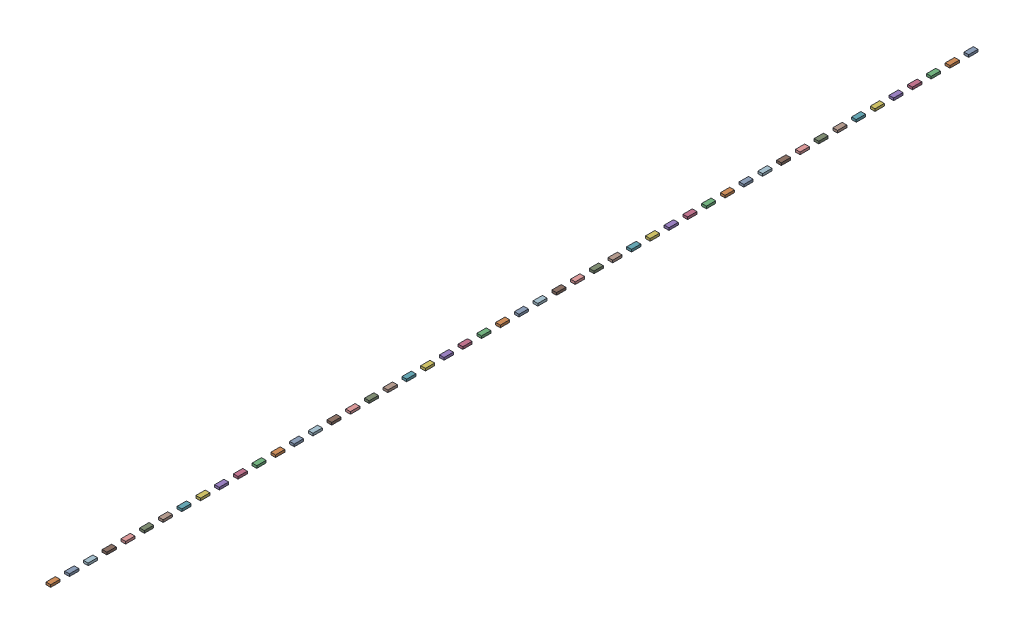
SolidWorks assembly lane_track_01, configuration Default. Lengths in mm.
Overall size (50 25 9900).
50 component instances, 1 part files, 0 mates.
Components (placement in the parent):
- lane-1: lane [Default] at (13.0249 -24.3771 9.6884) size (50 25 100)
- lane-2: lane [Default] at (13.0249 -24.3771 209.6884) size (50 25 100)
- lane-3: lane [Default] at (13.0249 -24.3771 409.6884) size (50 25 100)
- lane-4: lane [Default] at (13.0249 -24.3771 609.6884) size (50 25 100)
- lane-5: lane [Default] at (13.0249 -24.3771 809.6884) size (50 25 100)
- lane-6: lane [Default] at (13.0249 -24.3771 1009.6884) size (50 25 100)
- lane-7: lane [Default] at (13.0249 -24.3771 1209.6884) size (50 25 100)
- lane-8: lane [Default] at (13.0249 -24.3771 1409.6884) size (50 25 100)
- lane-9: lane [Default] at (13.0249 -24.3771 1609.6884) size (50 25 100)
- lane-10: lane [Default] at (13.0249 -24.3771 1809.6884) size (50 25 100)
- lane-11: lane [Default] at (13.0249 -24.3771 2009.6884) size (50 25 100)
- lane-12: lane [Default] at (13.0249 -24.3771 2209.6884) size (50 25 100)
- lane-13: lane [Default] at (13.0249 -24.3771 2409.6884) size (50 25 100)
- lane-14: lane [Default] at (13.0249 -24.3771 2609.6884) size (50 25 100)
- lane-15: lane [Default] at (13.0249 -24.3771 2809.6884) size (50 25 100)
- lane-16: lane [Default] at (13.0249 -24.3771 3009.6884) size (50 25 100)
- lane-17: lane [Default] at (13.0249 -24.3771 3209.6884) size (50 25 100)
- lane-18: lane [Default] at (13.0249 -24.3771 3409.6884) size (50 25 100)
- lane-19: lane [Default] at (13.0249 -24.3771 3609.6884) size (50 25 100)
- lane-20: lane [Default] at (13.0249 -24.3771 3809.6884) size (50 25 100)
- lane-21: lane [Default] at (13.0249 -24.3771 4009.6884) size (50 25 100)
- lane-22: lane [Default] at (13.0249 -24.3771 4209.6884) size (50 25 100)
- lane-23: lane [Default] at (13.0249 -24.3771 4409.6884) size (50 25 100)
- lane-24: lane [Default] at (13.0249 -24.3771 4609.6884) size (50 25 100)
- lane-25: lane [Default] at (13.0249 -24.3771 4809.6884) size (50 25 100)
- lane-26: lane [Default] at (13.0249 -24.3771 5009.6884) size (50 25 100)
- lane-27: lane [Default] at (13.0249 -24.3771 5209.6884) size (50 25 100)
- lane-28: lane [Default] at (13.0249 -24.3771 5409.6884) size (50 25 100)
- lane-29: lane [Default] at (13.0249 -24.3771 5609.6884) size (50 25 100)
- lane-30: lane [Default] at (13.0249 -24.3771 5809.6884) size (50 25 100)
- lane-31: lane [Default] at (13.0249 -24.3771 6009.6884) size (50 25 100)
- lane-32: lane [Default] at (13.0249 -24.3771 6209.6884) size (50 25 100)
- lane-33: lane [Default] at (13.0249 -24.3771 6409.6884) size (50 25 100)
- lane-34: lane [Default] at (13.0249 -24.3771 6609.6884) size (50 25 100)
- lane-35: lane [Default] at (13.0249 -24.3771 6809.6884) size (50 25 100)
- lane-36: lane [Default] at (13.0249 -24.3771 7009.6884) size (50 25 100)
- lane-37: lane [Default] at (13.0249 -24.3771 7209.6884) size (50 25 100)
- lane-38: lane [Default] at (13.0249 -24.3771 7409.6884) size (50 25 100)
- lane-39: lane [Default] at (13.0249 -24.3771 7609.6884) size (50 25 100)
- lane-40: lane [Default] at (13.0249 -24.3771 7809.6884) size (50 25 100)
- lane-41: lane [Default] at (13.0249 -24.3771 8009.6884) size (50 25 100)
- lane-42: lane [Default] at (13.0249 -24.3771 8209.6884) size (50 25 100)
- lane-43: lane [Default] at (13.0249 -24.3771 8409.6884) size (50 25 100)
- lane-44: lane [Default] at (13.0249 -24.3771 8609.6884) size (50 25 100)
- lane-45: lane [Default] at (13.0249 -24.3771 8809.6884) size (50 25 100)
- lane-46: lane [Default] at (13.0249 -24.3771 9009.6884) size (50 25 100)
- lane-47: lane [Default] at (13.0249 -24.3771 9209.6884) size (50 25 100)
- lane-48: lane [Default] at (13.0249 -24.3771 9409.6884) size (50 25 100)
- lane-49: lane [Default] at (13.0249 -24.3771 9609.6884) size (50 25 100)
- lane-50: lane [Default] at (13.0249 -24.3771 9809.6884) size (50 25 100)
